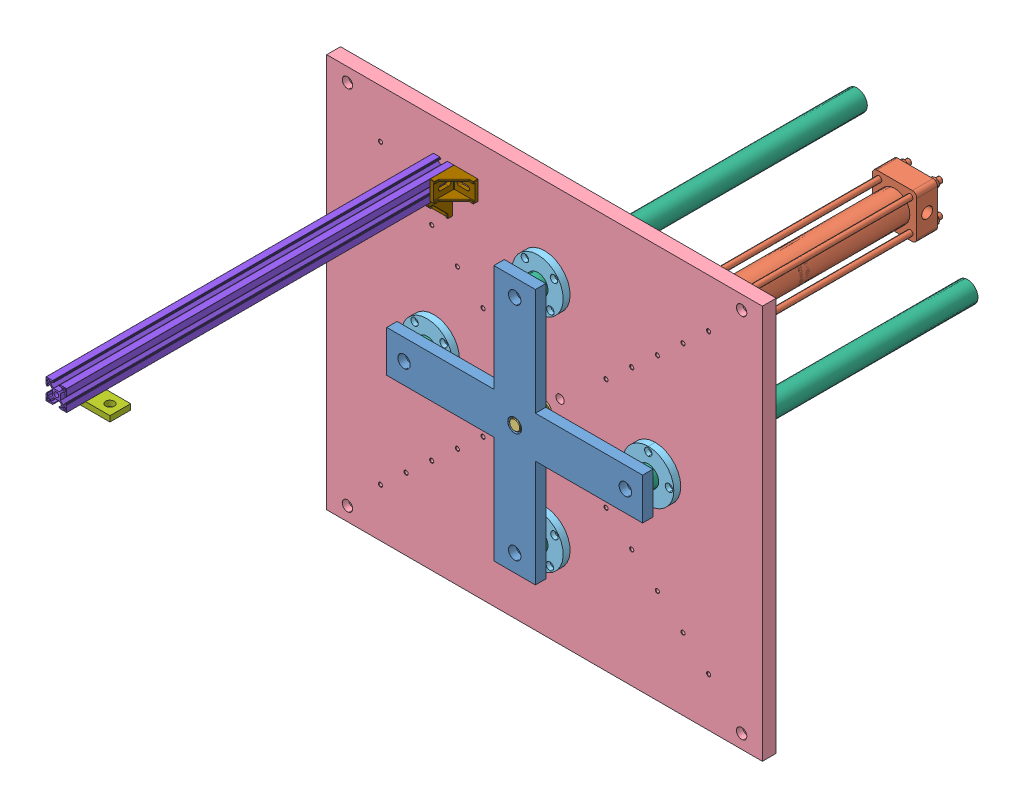
SolidWorks assembly 料盘, configuration 默认. Lengths in mm.
Overall size (630 570 1109.68).
17 component instances, 9 part files, 33 mates.
Components (placement in the parent):
- 十字形连接块-1: 十字形连接块 [默认] at (-590.974 -267.5355 362.5) size (370 370 15)
- MOB标准型中低压油缸[MOB-φ40×400]-1: MOB标准型中低压油缸[MOB-φ40×400] [MOB-φ40×400] at (-596.7877 -241.7796 328.0755) x (0 -1 0) z (0 0 1) size (64 64 592.86)
  - MOB标准型中低压油缸[MOB-φ40×400]_缸体-1: MOB标准型中低压油缸[MOB-φ40×400]_缸体 [默认] at (25.7559 5.8137 0) size (64 64 543.44)
  - MOB标准型中低压油缸[MOB-φ40×400]_杆-1: MOB标准型中低压油缸[MOB-φ40×400]_杆 [默认] at (25.7559 5.8137 4.4245) size (20 20 445)
- 放料盘底板-1: 放料盘底板 [默认] at (-590.974 -267.5355 334.3155) x (1 0 0) z (0 0 -1) size (630 570 20)
- LHFRR30-1: LHFRR30 [Default] at (-430.974 -267.5355 344.3155) x (0 0 -1) z (0 1 0) size (64 74 74)
- 导向轴-1: 导向轴 [默认] at (-430.974 -267.5355 362.5) x (0 0 -1) z (0.99986 -0.016757 0) size (480 30 30)
- 导向轴-2: 导向轴 [默认] at (-590.974 -427.5355 362.5) x (0 0 -1) z (0.379485 0.925198 0) size (480 30 30)
- LHFRR30-4: LHFRR30 [Default] at (-590.974 -427.5355 344.3155) x (0 0 -1) z (-0.587573 0.809171 0) size (64 74 74)
- 导向轴-4: 导向轴 [默认] at (-750.974 -267.5355 362.5) x (0 0 -1) z (-0.468143 -0.883653 0) size (480 30 30)
- LHFRR30-5: LHFRR30 [Default] at (-750.974 -267.5355 344.3155) x (0 0 -1) z (-0.597573 0.801814 0) size (64 74 74)
- LHFRR30-6: LHFRR30 [Default] at (-590.974 -107.5355 344.3155) x (0 0 -1) z (-0.613719 0.789524 0) size (64 74 74)
- 导向轴-5: 导向轴 [默认] at (-590.974 -107.5355 362.5) x (0 0 -1) z (-0.468265 -0.883588 0) size (480 30 30)
- 感应器板-1: 感应器板 [默认] at (-719.3817 -58.8457 851.8435) x (1 0 0) z (0 -1 0) size (65 30 8)
- 560铝型材-1: 560铝型材 [默认<按加工>] at (-736.8817 -43.8457 334.3155) x (0 0 1) z (-1 0 0) size (560 30 30)
- LBSB8-3030-1: LBSB8-3030 [默认] at (-737.8817 -58.8457 334.3155) x (0 0 1) z (1 0 0) size (37 37 28)
- LBSB8-3030-2: LBSB8-3030 [默认] at (-721.8817 -42.8457 334.3155) x (0 0 1) z (0 1 0) size (37 37 28)
Mates (geometry in assembly coordinates):
- 同心1: concentric anti-aligned: cylinder of 十字形连接块-1 through (-590.974 -267.5355 377.5) axis (0 0 1) radius 10; cylinder of MOB标准型中低压油缸[MOB-φ40×400]-1/MOB标准型中低压油缸[MOB-φ40×400]_杆-1 through (-590.974 -267.5355 -67.5) axis (0 0 -1) radius 8
- 同心2: concentric anti-aligned: cylinder of MOB标准型中低压油缸[MOB-φ40×400]-1/MOB标准型中低压油缸[MOB-φ40×400]_杆-1 through (-590.974 -267.5355 -67.5) axis (0 0 -1) radius 8; cylinder of 放料盘底板-1 through (-590.974 -267.5355 334.3155) axis (0 0 1) radius 10
- 重合3: coincident aligned: plane of 十字形连接块-1 through (-590.974 -267.5355 377.5) normal (0 0 1); plane of MOB标准型中低压油缸[MOB-φ40×400]-1/MOB标准型中低压油缸[MOB-φ40×400]_杆-1 through (-590.974 -267.5355 377.5) normal (0 0 1)
- 同心3: concentric aligned: cylinder of 十字形连接块-1 through (-590.974 -107.5355 377.5) axis (0 0 1) radius 9; cylinder of 放料盘底板-1 through (-590.974 -107.5355 334.3155) axis (0 0 1) radius 22.5
- 同心4: concentric anti-aligned: cylinder of MOB标准型中低压油缸[MOB-φ40×400]-1/MOB标准型中低压油缸[MOB-φ40×400]_缸体-1 through (-613.474 -290.0355 321.5155) axis (0 0 -1) radius 4; cylinder of 放料盘底板-1 through (-613.474 -290.0355 334.3155) axis (0 0 1) radius 6
- 重合6: coincident anti-aligned: plane of MOB标准型中低压油缸[MOB-φ40×400]-1/MOB标准型中低压油缸[MOB-φ40×400]_缸体-1 through (-606.5458 -290.0355 314.3155) normal (0 0 1); plane of 放料盘底板-1 through (-590.974 -267.5355 314.3155) normal (0 0 -1)
- 同心5: concentric anti-aligned: cylinder of 放料盘底板-1 through (-430.974 -267.5355 334.3155) axis (0 0 1) radius 22.5; cylinder of LHFRR30-1 through (-430.974 -267.5355 280.3155) axis (0 0 -1) radius 22.5
- 重合7: coincident anti-aligned: plane of 放料盘底板-1 through (-590.974 -267.5355 334.3155) normal (0 0 1); plane of LHFRR30-1 through (-452.974 -267.5355 334.3155) normal (0 0 -1)
- 同心6: concentric anti-aligned: cylinder of LHFRR30-1 through (-430.974 -267.5355 280.3155) axis (0 0 -1) radius 15; cylinder of 导向轴-1 through (-430.974 -267.5355 362.5) axis (0 0 1) radius 15
- 重合8: coincident anti-aligned: plane of 十字形连接块-1 through (-590.974 -267.5355 362.5) normal (0 0 -1); plane of 导向轴-1 through (-430.974 -267.5355 362.5) normal (0 0 1)
- 同心7: concentric anti-aligned: cylinder of 放料盘底板-1 through (-430.974 -297.5355 334.3155) axis (0 0 1) radius 2.5; cylinder of LHFRR30-1 through (-430.974 -297.5355 334.3155) axis (0 0 -1) radius 5.5
- 平行1: parallel aligned: cylinder of 放料盘底板-1 through (-590.974 -427.5355 334.3155) axis (0 0 1) radius 22.5; cylinder of 导向轴-2 through (-590.974 -427.5355 362.5) axis (0 0 1) radius 15
- 同心12: concentric anti-aligned: cylinder of 放料盘底板-1 through (-590.974 -427.5355 334.3155) axis (0 0 1) radius 22.5; cylinder of LHFRR30-4 through (-590.974 -427.5355 280.3155) axis (0 0 -1) radius 22.5
- 重合10: coincident: line of 放料盘底板-1 through (-275.974 -552.5355 334.3155) axis (-1 0 0); plane of LHFRR30-4 through (-608.7758 -440.4621 334.3155) normal (0 0 -1)
- 同心13: concentric anti-aligned: cylinder of 导向轴-2 through (-590.974 -427.5355 362.5) axis (0 0 1) radius 15; cylinder of LHFRR30-4 through (-590.974 -427.5355 280.3155) axis (0 0 -1) radius 22.5
- 重合12: coincident anti-aligned: plane of 十字形连接块-1 through (-590.974 -267.5355 362.5) normal (0 0 -1); plane of 导向轴-2 through (-590.974 -427.5355 362.5) normal (0 0 1)
- 同心14: concentric anti-aligned: cylinder of 放料盘底板-1 through (-750.974 -267.5355 334.3155) axis (0 0 1) radius 22.5; cylinder of LHFRR30-5 through (-750.974 -267.5355 280.3155) axis (0 0 -1) radius 22.5
- 重合13: coincident anti-aligned: plane of 放料盘底板-1 through (-590.974 -267.5355 334.3155) normal (0 0 1); plane of LHFRR30-5 through (-768.614 -280.6822 334.3155) normal (0 0 -1)
- 同心15: concentric anti-aligned: cylinder of 导向轴-4 through (-750.974 -267.5355 362.5) axis (0 0 1) radius 15; cylinder of LHFRR30-5 through (-750.974 -267.5355 280.3155) axis (0 0 -1) radius 15
- 重合14: coincident anti-aligned: plane of 十字形连接块-1 through (-590.974 -267.5355 362.5) normal (0 0 -1); plane of 导向轴-4 through (-750.974 -267.5355 362.5) normal (0 0 1)
- 同心16: concentric anti-aligned: cylinder of 放料盘底板-1 through (-590.974 -107.5355 334.3155) axis (0 0 1) radius 22.5; cylinder of LHFRR30-6 through (-590.974 -107.5355 280.3155) axis (0 0 -1) radius 22.5
- 重合15: coincident anti-aligned: plane of 放料盘底板-1 through (-590.974 -267.5355 334.3155) normal (0 0 1); plane of LHFRR30-6 through (-608.3436 -121.0374 334.3155) normal (0 0 -1)
- 同心17: concentric anti-aligned: cylinder of LHFRR30-6 through (-590.974 -107.5355 280.3155) axis (0 0 -1) radius 15; cylinder of 导向轴-5 through (-590.974 -107.5355 362.5) axis (0 0 1) radius 15
- 重合16: coincident anti-aligned: plane of 十字形连接块-1 through (-590.974 -267.5355 362.5) normal (0 0 -1); plane of 导向轴-5 through (-590.974 -107.5355 362.5) normal (0 0 1)
- 重合18: coincident anti-aligned: plane of 放料盘底板-1 through (-590.974 -267.5355 334.3155) normal (0 0 1); plane of 560铝型材-1 through (-742.9817 -47.9658 334.3155) normal (0 0 -1)
- 重合19: coincident anti-aligned: plane of 感应器板-1 through (-719.3817 -58.8457 851.8435) normal (0 1 0); plane of 560铝型材-1 through (-731.3817 -58.8457 894.3155) normal (0 -1 0)
- 重合20: coincident anti-aligned: plane of 放料盘底板-1 through (-590.974 -267.5355 334.3155) normal (0 0 1); plane of LBSB8-3030-1 through (-723.8817 -93.8457 334.3155) normal (0 0 -1)
- 重合21: coincident anti-aligned: plane of 560铝型材-1 through (-751.6817 -58.8457 894.3155) normal (0 -1 0); plane of LBSB8-3030-1 through (-723.8817 -58.8457 334.3155) normal (0 1 0)
- 重合22: coincident aligned: plane of 560铝型材-1 through (-751.8817 -49.3457 894.3155) normal (-1 0 0); plane of LBSB8-3030-1 through (-751.8817 -58.8457 334.3155) normal (-1 0 0)
- 重合23: coincident anti-aligned: plane of 560铝型材-1 through (-721.8817 -38.3457 894.3155) normal (1 0 0); plane of LBSB8-3030-2 through (-721.8817 -28.8457 334.3155) normal (-1 0 0)
- 重合24: coincident aligned: plane of 560铝型材-1 through (-722.0817 -28.8457 894.3155) normal (0 1 0); plane of LBSB8-3030-2 through (-721.8817 -28.8457 334.3155) normal (0 1 0)
- 重合25: coincident anti-aligned: plane of 放料盘底板-1 through (-590.974 -267.5355 334.3155) normal (0 0 1); plane of LBSB8-3030-2 through (-686.8817 -28.8457 334.3155) normal (0 0 -1)
- 宽度1: width: plane of 560铝型材-1 through (-740.9817 -57.5457 894.3155) normal (1 0 0); plane of 感应器板-1 through (-732.7817 -56.9457 894.3155) normal (-1 0 0); cylinder of 560铝型材-1 through (-736.8817 -66.8457 851.8435) axis (0 -1 0) radius 3.3
